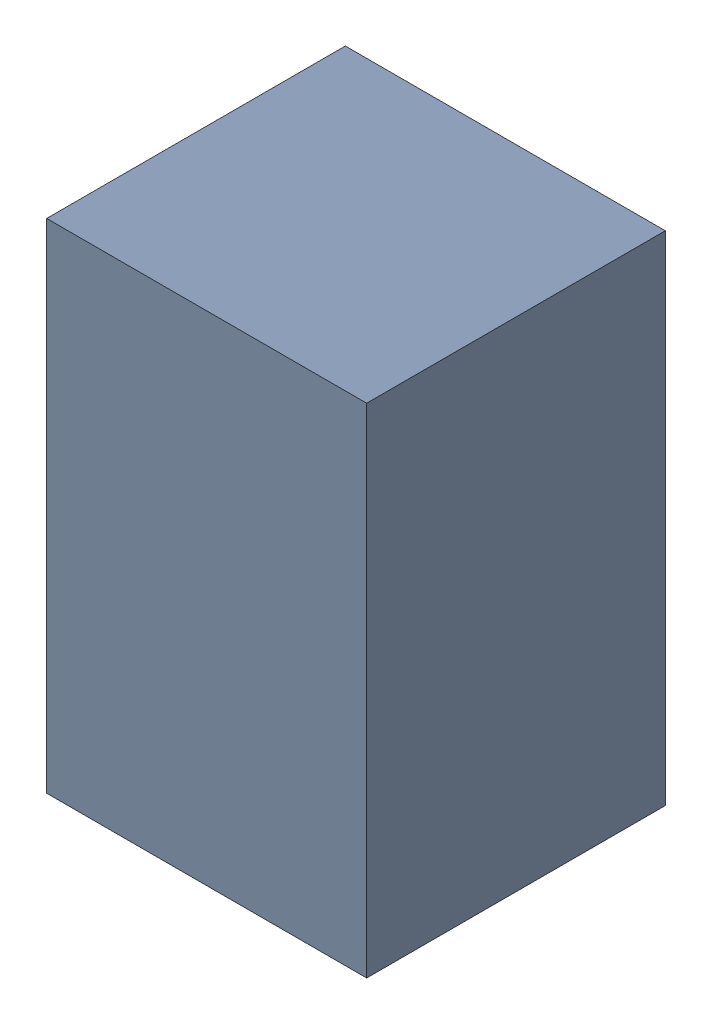
SolidWorks assembly C11, configuration Default. Lengths in mm.
Overall size (1.35 2.1 1.26).
2 component instances, 1 part files, 0 mates.
Components (placement in the parent):
- 407985696-1: 407985696 [Default] at (33.274 69.723 0.0127) size (1.35 2.1 1.26)
  - Extruded_1-1: Extruded_1 [Default] at origin size (1.35 2.1 1.26)
